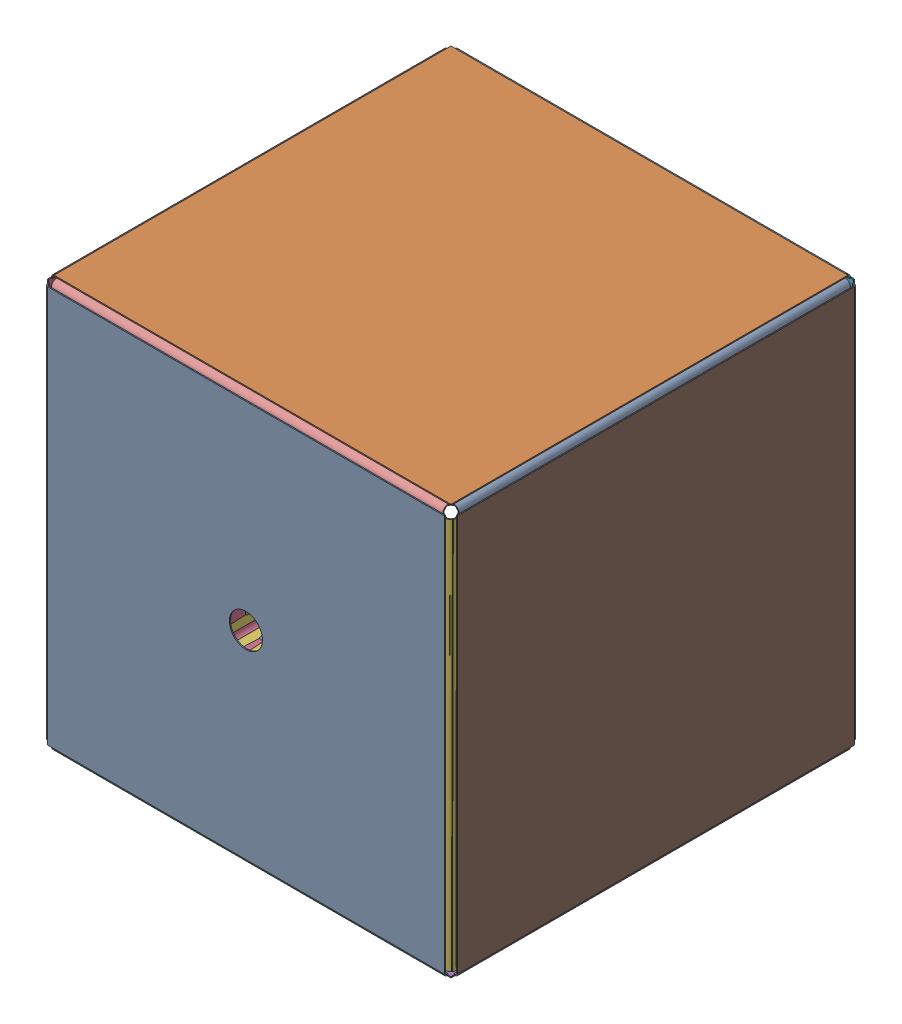
SolidWorks assembly outer_layer, configuration Default. Lengths in mm.
Overall size (744 744 742).
26 component instances, 3 part files, 14 mates.
Components (placement in the parent):
- outer_flat_front-2: outer_flat_front [Default] at (0 0 372) x (-1 0 0) z (0 0 -1) size (720 720 4) (hidden)
- outer_bracket-5: outer_bracket [Default] at (-368 0 313) x (-1 0 0) z (0 0 -1) size (57 710 57)
- outer_bracket-6: outer_bracket [Default] at (0 -313 368) x (0 0 1) z (0 1 0) size (57 710 57)
- outer_flat-1: outer_flat [Default] at (-370 0 0) x (0 0 1) z (-1 0 0) size (720 720 4)
- outer_flat-2: outer_flat [Default] at (0 -370 0) x (1 0 0) z (0 -1 0) size (720 720 4)
- outer_bracket-7: outer_bracket [Default] at (-313 -368 0) x (0 -1 0) z (1 0 0) size (57 710 57)
- outer_flat-7: outer_flat [Default] at (0 0 -370) x (-1 0 0) z (0 0 -1) size (720 720 4)
- outer_bracket-8: outer_bracket [Default] at (-368 0 -313) x (-1 0 0) z (0 0 1) size (57 710 57)
- outer_bracket-9: outer_bracket [Default] at (368 0 313) x (1 0 0) z (0 0 -1) size (57 710 57)
- outer_bracket-10: outer_bracket [Default] at (368 0 -313) size (57 710 57)
- outer_flat-3: outer_flat [Default] at (370 0 0) x (0 0 -1) z (1 0 0) size (720 720 4)
- outer_bracket-11: outer_bracket [Default] at (313 -368 0) x (0 -1 0) z (-1 0 0) size (57 710 57)
- outer_bracket-12: outer_bracket [Default] at (-368 0 -313) x (-1 0 0) z (0 0 1) size (57 710 57)
- outer_bracket-13: outer_bracket [Default] at (-368 0 313) x (-1 0 0) z (0 0 -1) size (57 710 57)
- outer_flat-4: outer_flat [Default] at (-370 0 0) x (0 0 1) z (-1 0 0) size (720 720 4)
- outer_bracket-14: outer_bracket [Default] at (-313 -368 0) x (0 -1 0) z (1 0 0) size (57 710 57)
- outer_bracket-15: outer_bracket [Default] at (368 0 -313) size (57 710 57)
- outer_bracket-16: outer_bracket [Default] at (368 0 313) x (1 0 0) z (0 0 -1) size (57 710 57)
- outer_flat-5: outer_flat [Default] at (370 0 0) x (0 0 -1) z (1 0 0) size (720 720 4)
- outer_bracket-17: outer_bracket [Default] at (313 -368 0) x (0 -1 0) z (-1 0 0) size (57 710 57)
- outer_bracket-18: outer_bracket [Default] at (0 -313 -368) x (0 0 -1) z (0 1 0) size (57 710 57)
- outer_bracket-19: outer_bracket [Default] at (0 313 368) x (0 0 1) z (0 -1 0) size (57 710 57)
- outer_bracket-20: outer_bracket [Default] at (-313 368 0) x (0 1 0) z (1 0 0) size (57 710 57)
- outer_bracket-21: outer_bracket [Default] at (0 313 -368) x (0 0 -1) z (0 -1 0) size (57 710 57)
- outer_bracket-22: outer_bracket [Default] at (313 368 0) x (0 1 0) z (-1 0 0) size (57 710 57)
- outer_flat-6: outer_flat [Default] at (0 370 0) x (-1 0 0) z (0 1 0) size (720 720 4)
Mates (geometry in assembly coordinates):
- Coincident19: coincident anti-aligned: plane of outer_flat_front-2 through (0 0 370) normal (0 0 -1); plane of outer_bracket-5 through (-370 0 370) normal (0 0 1)
- Coincident20: coincident anti-aligned: plane of outer_flat_front-2 through (0 0 370) normal (0 0 -1); plane of outer_bracket-6 through (0 -313 370) normal (0 0 1)
- Concentric8: concentric anti-aligned: circle of outer_flat_front-2; circle of outer_bracket-6
- Concentric9: concentric aligned: circle of outer_flat_front-2; circle of outer_bracket-5
- Coincident23: coincident anti-aligned: plane of outer_bracket-6 through (0 -370 370) normal (0 -1 0); plane of outer_flat-2 through (0 -370 0) normal (0 1 0)
- Concentric10: concentric aligned: circle of outer_bracket-6; circle of outer_flat-2
- Coincident25: coincident anti-aligned: plane of outer_bracket-5 through (-370 0 313) normal (-1 0 0); plane of outer_flat-1 through (-370 0 0) normal (1 0 0)
- Concentric11: concentric anti-aligned: circle of outer_bracket-5; circle of outer_flat-1
- Coincident27: coincident anti-aligned: plane of outer_flat-2 through (0 -370 0) normal (0 1 0); plane of outer_bracket-7 through (-313 -370 0) normal (0 -1 0)
- Coincident28: coincident anti-aligned: plane of outer_flat-1 through (-370 0 0) normal (1 0 0); plane of outer_bracket-7 through (-370 -370 0) normal (-1 0 0)
- Concentric12: concentric anti-aligned: circle of outer_flat-2; circle of outer_bracket-7
- Concentric13: concentric anti-aligned: circle of outer_bracket-21; circle of outer_flat-7
- Concentric14: concentric aligned: circle of outer_bracket-12; circle of outer_flat-7
- Coincident33: coincident anti-aligned: plane of outer_bracket-21 through (0 313 -370) normal (0 0 -1); plane of outer_flat-7 through (0 0 -370) normal (0 0 1)
